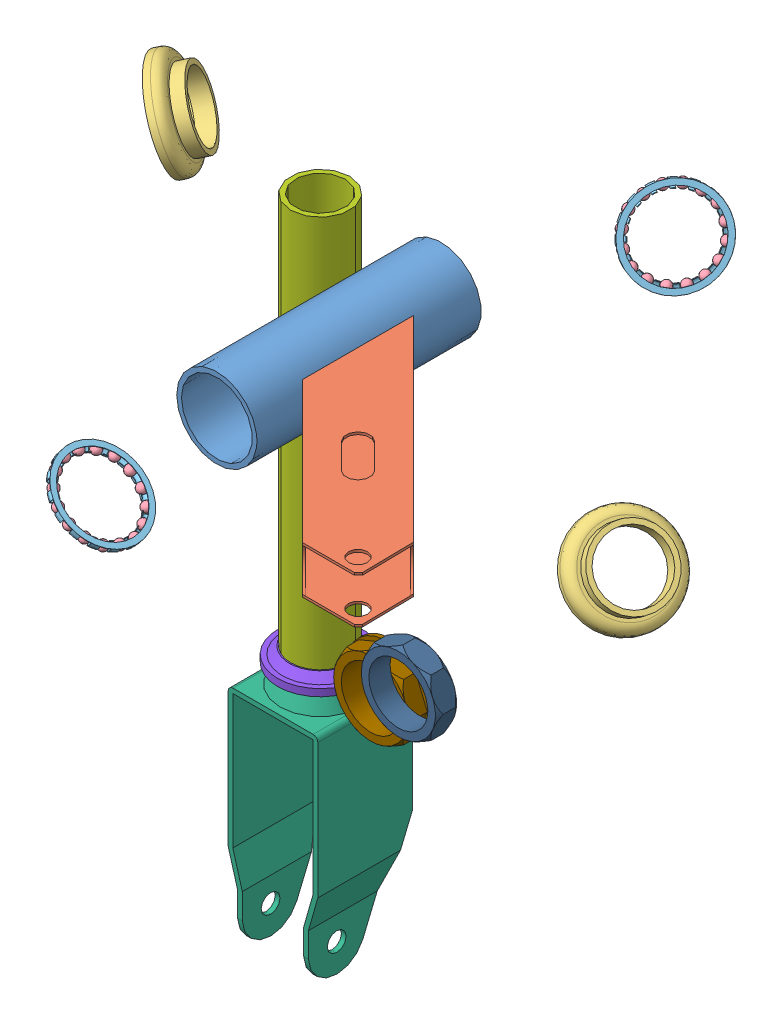
SolidWorks assembly moyeu fourche, configuration Default. Lengths in mm.
Overall size (178.47 364 366.03).
47 component instances, 11 part files, 0 mates.
Components (placement in the parent):
- tube moyeu-1: tube moyeu [Default] at (-26.9875 -32.7389 0) size (34 34 95)
- equerre-1: equerre [Default] at (0.1029 -0.1829 -0.2778) x (-1 0 0) z (0 1 0) size (83.49 106.89 20)
- cloche roulement-1: cloche roulement [Default] at (72.0201 -81.0266 -47.979) x (-0.610666 0.374538 0.697717) z (-0.32145 0.68798 -0.650656) size (40.51 11.62 40.51)
- cloche roulement-2: cloche roulement [Default] at (-50.8231 42.7985 -26.4845) x (0.634109 -0.607589 0.478269) z (0.197128 0.72511 0.659815) size (40.51 11.62 40.51)
- roulement moyeu-1: roulement moyeu [Default] at (-2.5682 -38.567 -122.1781) x (0.16974 -0.907076 0.385229) z (0.620723 -0.20521 -0.756698) size (47.2 143.38 46.51)
  - bille-1: bille [Default] at (-16.3235 0.9699 0.0106) x (0.344984 -0.922949 -0.170735) z (0.079352 -0.152572 0.985102) size (4 4 4)
  - cage-1: cage [Default] at origin size (36.4 3.55 36.4)
  - bille-2: bille [Default] at (-6.0395 0.9699 14.7134) size (4 4 4)
  - bille-3: bille [Default] at (-11.4914 0.9699 11.4269) x (0.999917 -0.012878 -0.000163) z (-0.000163 -0.025274 0.999681) size (4 4 4)
  - bille-4: bille [Default] at (-14.8041 0.9699 6.1758) size (4 4 4)
  - bille-5: bille [Default] at (-6.3389 0.9699 -15.2062) size (4 4 4)
  - bille-6: bille [Default] at (6.0934 0.9699 14.7096) size (4 4 4)
  - bille-7: bille [Default] at (14.5997 0.9699 6.138) size (4 4 4)
  - bille-8: bille [Default] at (11.1504 0.9699 11.2899) size (4 4 4)
  - bille-9: bille [Default] at (15.7192 0.9699 -0.0149) size (4 4 4)
  - bille-10: bille [Default] at (-11.4442 0.9699 -11.3654) x (0.89969 -0.394287 -0.187339) z (-0.174381 -0.718048 0.673794) size (4 4 4)
  - bille-11: bille [Default] at (-15.1159 0.9699 -6.0673) size (4 4 4)
  - bille-12: bille [Default] at (-0.1255 0.9699 -16.2249) size (4 4 4)
  - bille-13: bille [Default] at (-0.1376 0.9699 16.1353) size (4 4 4)
  - bille-14: bille [Default] at (14.5011 0.9699 -6.2064) size (4 4 4)
  - bille-15: bille [Default] at (11.268 0.9699 -11.4574) size (4 4 4)
  - bille-16: bille [Default] at (6.0958 0.9699 -14.8703) x (0.607872 0.788579 0.092924) z (0.040029 -0.147312 0.98828) size (4 4 4)
- roulement moyeu-2: roulement moyeu [Default] at (-0.7879 -10.5274 122.8491) x (-0.419161 0.408768 0.810687) z (0.666239 -0.468116 0.580511) size (47.2 143.38 46.51)
  - bille-1: bille [Default] at (-16.3235 0.9699 0.0106) x (0.344984 -0.922949 -0.170735) z (0.079352 -0.152572 0.985102) size (4 4 4)
  - cage-1: cage [Default] at origin size (36.4 3.55 36.4)
  - bille-2: bille [Default] at (-6.0395 0.9699 14.7134) size (4 4 4)
  - bille-3: bille [Default] at (-11.4914 0.9699 11.4269) x (0.999917 -0.012878 -0.000163) z (-0.000163 -0.025274 0.999681) size (4 4 4)
  - bille-4: bille [Default] at (-14.8041 0.9699 6.1758) size (4 4 4)
  - bille-5: bille [Default] at (-6.3389 0.9699 -15.2062) size (4 4 4)
  - bille-6: bille [Default] at (6.0934 0.9699 14.7096) size (4 4 4)
  - bille-7: bille [Default] at (14.5997 0.9699 6.138) size (4 4 4)
  - bille-8: bille [Default] at (11.1504 0.9699 11.2899) size (4 4 4)
  - bille-9: bille [Default] at (15.7192 0.9699 -0.0149) size (4 4 4)
  - bille-10: bille [Default] at (-11.4442 0.9699 -11.3654) x (0.89969 -0.394287 -0.187339) z (-0.174381 -0.718048 0.673794) size (4 4 4)
  - bille-11: bille [Default] at (-15.1159 0.9699 -6.0673) size (4 4 4)
  - bille-12: bille [Default] at (-0.1255 0.9699 -16.2249) size (4 4 4)
  - bille-13: bille [Default] at (-0.1376 0.9699 16.1353) size (4 4 4)
  - bille-14: bille [Default] at (14.5011 0.9699 -6.2064) size (4 4 4)
  - bille-15: bille [Default] at (11.268 0.9699 -11.4574) size (4 4 4)
  - bille-16: bille [Default] at (6.0958 0.9699 -14.8703) x (0.607872 0.788579 0.092924) z (0.040029 -0.147312 0.98828) size (4 4 4)
- bouton de manoeuvre-1: bouton de manoeuvre [Default] at (24.7218 -32.7389 16.2093) x (0.707107 0 0.707107) z (0 1 0)
- support roue-1: support roue [Défaut] at (-87.7887 -214.9831 -57.0987) size (38 275 40)
  - fourche-1: fourche [Défaut] at origin size (38 103 40)
  - tube pivot-1: tube pivot [Défaut] at origin size (25 180 25)
  - bague arrêt-1: bague arrêt [Default] at origin size (36 6 36)
- écrou octo 1-1: écrou octo 1 [Default] at (-12.5798 -153.7735 -14.2878) size (36.41 36.91 11)
- écrou octo 2-1: écrou octo 2 [Default] at (20.3937 -125.0146 8.9987) size (36.41 36.91 9)
